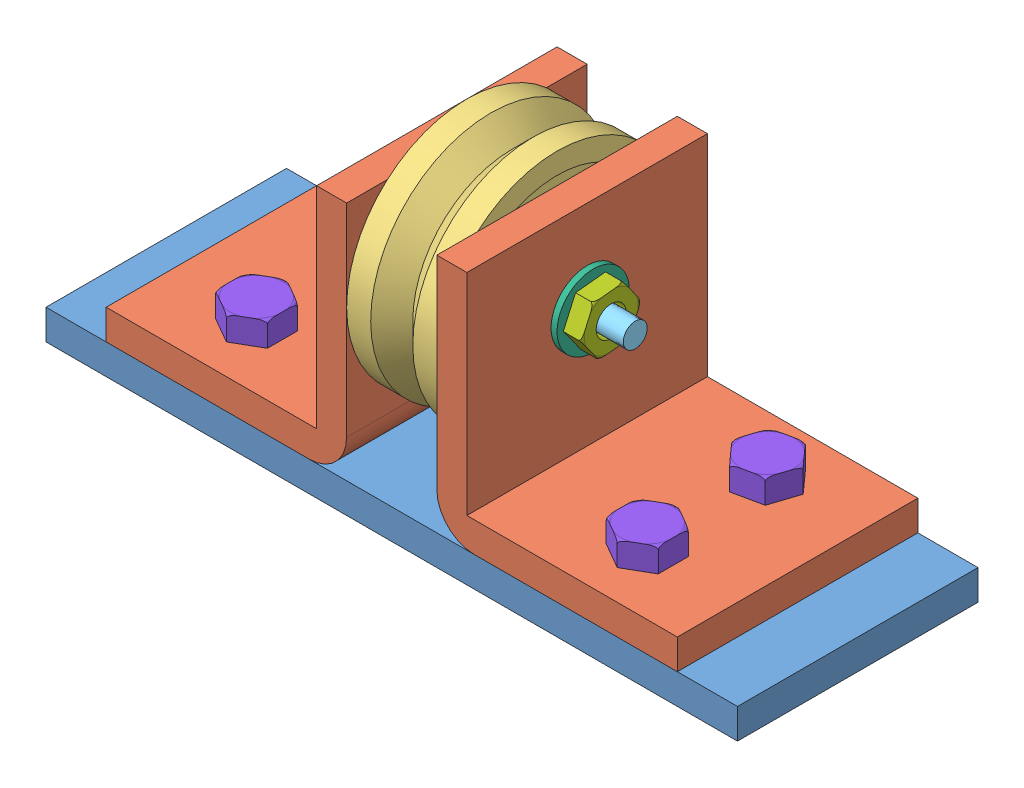
SolidWorks assembly Assem3, configuration Default. Lengths in mm.
Overall size (2921 1416.61 1309.23).
13 component instances, 8 part files, 26 mates.
Components (placement in the parent):
- box-1: box [Default] at (1153.6627 1195.6797 2388.8425) size (2921 127 1016)
- support-1: support [Default] at (-52.8373 1449.6797 2896.8425) size (1016 1016 1016)
- support-2: support [Default] at (2360.1627 1449.6797 1880.8425) x (-1 0 0) z (0 0 -1) size (1016 1016 1016)
- wheel-1: wheel [Default] at (963.1627 1957.6797 2388.8425) x (1 0 0) z (0 0.352977 0.935632) size (381 1016 1016)
- bushing-1: bushing [Default] at (836.1627 1957.6797 2388.8425) x (0 -1 0) z (0 0 1) size (254 127 254)
- bushing-2: bushing [Default] at (1344.1627 1957.6797 2388.8425) x (0 -1 0) z (0 0 1) size (254 127 254)
- shoulder screw-1: shoulder screw [Default] at (734.5627 1957.6797 2388.8425) x (0 -0.088135 0.996109) z (0 0.996109 0.088135) size (254 939.8 254)
- washer-1: washer [Default] at (1471.1627 1957.6797 2388.8425) x (0 -1 0) z (0 0 1) size (304.8 25.4 304.8)
- nut-1: nut [Default] at (1471.1627 1957.6797 2388.8425) x (0 -0.99473 -0.102528) z (0 -0.102528 0.99473) size (226.78 106.51 260.81)
- bolt-1: bolt [Default] at (1979.1627 1449.6797 2642.8425) size (228.18 334.3 262.21)
- bolt-2: bolt [Default] at (1979.1627 1449.6797 2134.8425) x (-0.205796 0 -0.978595) z (0.978595 0 -0.205796) size (228.18 334.3 262.21)
- bolt-3: bolt [Default] at (328.1627 1449.6797 2642.8425) size (228.18 334.3 262.21)
- bolt-4: bolt [Default] at (328.1627 1449.6797 2134.8425) size (228.18 334.3 262.21)
Mates (geometry in assembly coordinates):
- Concentric1: concentric anti-aligned: cylinder of box-1 through (328.1627 1322.6797 2642.8425) axis (0 -1 0) radius 63.5; cylinder of support-1 through (328.1627 433.6797 2642.8425) axis (0 1 0) radius 63.5
- Concentric2: concentric aligned: circle of box-1; circle of support-1
- Coincident2: coincident anti-aligned: plane of box-1 through (1153.6627 1322.6797 2388.8425) normal (0 1 0); plane of support-1 through (804.4127 1322.6797 1880.8425) normal (0 -1 0)
- Concentric3: concentric anti-aligned: cylinder of box-1 through (1979.1627 1322.6797 2134.8425) axis (0 -1 0) radius 63.5; cylinder of support-2 through (1979.1627 433.6797 2134.8425) axis (0 1 0) radius 63.5
- Concentric4: concentric anti-aligned: cylinder of box-1 through (1979.1627 1322.6797 2642.8425) axis (0 -1 0) radius 63.5; circle of support-2
- Coincident3: coincident anti-aligned: plane of box-1 through (1153.6627 1322.6797 2388.8425) normal (0 1 0); plane of support-2 through (1502.9127 1322.6797 2896.8425) normal (0 -1 0)
- Concentric5: concentric aligned: circle of support-1; circle of wheel-1
- Coincident4: coincident anti-aligned: plane of support-2 through (1344.1627 2338.6797 2896.8425) normal (-1 0 0); plane of wheel-1 through (1344.1627 2031.9455 2360.825) normal (1 0 0)
- Concentric6: concentric anti-aligned: circle of support-1; circle of bushing-1
- Coincident5: coincident anti-aligned: plane of wheel-1 through (963.1627 2076.5049 2344.0144) normal (-1 0 0); plane of bushing-1 through (963.1627 1957.6797 2388.8425) normal (1 0 0)
- Concentric7: concentric anti-aligned: circle of support-2; cylinder of bushing-2 through (1471.1627 1957.6797 2388.8425) axis (-1 0 0) radius 79.375
- Coincident6: coincident anti-aligned: plane of wheel-1 through (1344.1627 2031.9455 2360.825) normal (1 0 0); plane of bushing-2 through (1344.1627 1957.6797 2388.8425) normal (-1 0 0)
- Concentric8: concentric anti-aligned: cylinder of bushing-1 through (963.1627 1957.6797 2388.8425) axis (-1 0 0) radius 79.375; circle of shoulder screw-1
- Coincident7: coincident anti-aligned: plane of support-1 through (836.1627 1449.6797 1880.8425) normal (-1 0 0); plane of shoulder screw-1 through (836.1627 1957.6797 2388.8425) normal (1 0 0)
- Concentric9: concentric anti-aligned: circle of shoulder screw-1; cylinder of washer-1 through (1496.5627 1957.6797 2388.8425) axis (-1 0 0) radius 152.4
- Coincident8: coincident anti-aligned: plane of support-2 through (1471.1627 1449.6797 2896.8425) normal (1 0 0); plane of washer-1 through (1471.1627 1957.6797 2388.8425) normal (-1 0 0)
- Concentric13: concentric aligned: circle of shoulder screw-1; cylinder of nut-1 through (1471.1627 1957.6797 2388.8425) axis (1 0 0) radius 63.5
- Coincident12: coincident anti-aligned: circle of support-2; plane of nut-1 through (1471.1627 1957.6797 2388.8425) normal (-1 0 0)
- Concentric14: concentric anti-aligned: circle of support-2; circle of bolt-1
- Coincident15: coincident aligned: circle of support-2; cylinder of bolt-2 through (1979.1627 1221.0797 2134.8425) axis (0 1 0) radius 63.5
- Coincident16: coincident aligned: circle of support-1; cylinder of bolt-3 through (328.1627 1221.0797 2642.8425) axis (0 1 0) radius 63.5
- Concentric15: concentric aligned: circle of support-1; cylinder of bolt-4 through (328.1627 1221.0797 2134.8425) axis (0 1 0) radius 63.5
- Coincident17: coincident anti-aligned: plane of support-2 through (2360.1627 1449.6797 2896.8425) normal (0 1 0); plane of bolt-1 through (1979.1627 1449.6797 2642.8425) normal (0 -1 0)
- Coincident18: coincident anti-aligned: plane of support-1 through (-52.8373 1449.6797 1880.8425) normal (0 1 0); plane of bolt-3 through (328.1627 1449.6797 2642.8425) normal (0 -1 0)
- Coincident19: coincident anti-aligned: plane of support-1 through (-52.8373 1449.6797 1880.8425) normal (0 1 0); plane of bolt-4 through (328.1627 1449.6797 2134.8425) normal (0 -1 0)
- Coincident20: coincident anti-aligned: plane of support-2 through (2360.1627 1449.6797 2896.8425) normal (0 1 0); plane of bolt-2 through (1979.1627 1449.6797 2134.8425) normal (0 -1 0)
